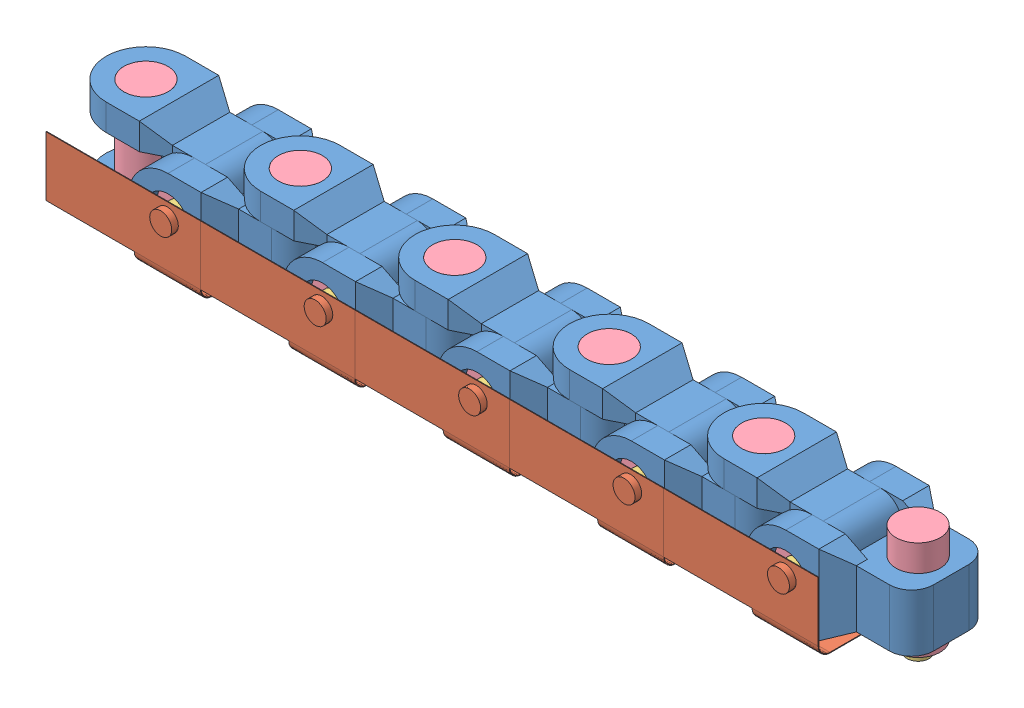
SolidWorks assembly Assem1, configuration Default. Lengths in mm.
Overall size (385.2 53.3 53.3).
48 component instances, 4 part files, 59 mates.
Components (placement in the parent):
- Joint 1-1: Joint 1 [Default] at (-1.5534 8.3861 59.3933) size (68 50 36)
- Joint 1-2: Joint 1 [Default] at (33.4466 33.3861 84.3933) x (1 0 0) z (0 1 0) size (68 50 36)
- Joint 1-3: Joint 1 [Default] at (68.4466 8.3861 59.3933) size (68 50 36)
- Joint 1-4: Joint 1 [Default] at (103.4466 33.3861 84.3933) x (1 0 0) z (0 1 0) size (68 50 36)
- Joint 1-5: Joint 1 [Default] at (138.4466 8.3861 59.3933) size (68 50 36)
- Joint 1-6: Joint 1 [Default] at (173.4466 33.3861 84.3933) x (1 0 0) z (0 1 0) size (68 50 36)
- Joint 1-7: Joint 1 [Default] at (208.4466 8.3861 59.3933) size (68 50 36)
- Joint 1-8: Joint 1 [Default] at (243.4466 33.3861 84.3933) x (1 0 0) z (0 1 0) size (68 50 36)
- Joint 1-9: Joint 1 [Default] at (278.4466 8.3861 59.3933) size (68 50 36)
- Joint 1-10: Joint 1 [Default] at (313.4466 33.3861 84.3933) x (1 0 0) z (0 1 0) size (68 50 36)
- PCB 1-1: PCB 1 [Default] at (264.8403 8.3861 45.5481) x (-1 0 0) z (0 0 1) size (70 35.3 43.3)
- PCB 1-2: PCB 1 [Default] at (194.8403 8.3861 45.5481) x (-1 0 0) z (0 0 1) size (70 35.3 43.3)
- PCB 1-3: PCB 1 [Default] at (124.8403 8.3861 45.5481) x (-1 0 0) z (0 0 1) size (70 35.3 43.3)
- PCB 1-4: PCB 1 [Default] at (54.8403 8.3861 45.5481) x (-1 0 0) z (0 0 1) size (70 35.3 43.3)
- PCB 1-5: PCB 1 [Default] at (-15.1597 8.3861 45.5481) x (-1 0 0) z (0 0 1) size (70 35.3 43.3)
- Magnet and Dowel 1-1: Magnet and Dowel 1 [Default] at (5.0839 18.1514 56.3077) x (-0.837169 0 -0.546944) z (-0.546944 0 0.837169) size (21.97 50 21.97)
  - Magnet 1-1: Magnet 1 [Default] at (3.8689 4.7653 6.2135) size (10 5 10)
  - Dowel 1-1: Dowel 1 [Default] at (3.8689 -40.2347 6.2135) x (0.994608 0 -0.103709) z (0.103709 0 0.994608) size (20 45 20)
- Magnet and Dowel 1-2: Magnet and Dowel 1 [Default] at (285.0839 18.1514 56.3077) x (-0.837169 0 -0.546944) z (-0.546944 0 0.837169) size (21.97 50 21.97)
  - Magnet 1-1: Magnet 1 [Default] at (3.8689 4.7653 6.2135) size (10 5 10)
  - Dowel 1-1: Dowel 1 [Default] at (3.8689 -40.2347 6.2135) x (0.994608 0 -0.103709) z (0.103709 0 0.994608) size (20 45 20)
- Magnet and Dowel 1-3: Magnet and Dowel 1 [Default] at (29.5777 39.5995 74.628) x (1 0 0) z (0 -1 0) size (21.97 50 21.97)
  - Magnet 1-1: Magnet 1 [Default] at (3.8689 4.7653 6.2135) size (10 5 10)
  - Dowel 1-1: Dowel 1 [Default] at (3.8689 -40.2347 6.2135) x (0.994608 0 -0.103709) z (0.103709 0 0.994608) size (20 45 20)
- Magnet and Dowel 1-4: Magnet and Dowel 1 [Default] at (215.0839 18.1514 56.3077) x (-0.837169 0 -0.546944) z (-0.546944 0 0.837169) size (21.97 50 21.97)
  - Magnet 1-1: Magnet 1 [Default] at (3.8689 4.7653 6.2135) size (10 5 10)
  - Dowel 1-1: Dowel 1 [Default] at (3.8689 -40.2347 6.2135) x (0.994608 0 -0.103709) z (0.103709 0 0.994608) size (20 45 20)
- Magnet and Dowel 1-5: Magnet and Dowel 1 [Default] at (75.0839 18.1514 56.3077) x (-0.837169 0 -0.546944) z (-0.546944 0 0.837169) size (21.97 50 21.97)
  - Magnet 1-1: Magnet 1 [Default] at (3.8689 4.7653 6.2135) size (10 5 10)
  - Dowel 1-1: Dowel 1 [Default] at (3.8689 -40.2347 6.2135) x (0.994608 0 -0.103709) z (0.103709 0 0.994608) size (20 45 20)
- Magnet and Dowel 1-6: Magnet and Dowel 1 [Default] at (99.5777 39.5995 74.628) x (1 0 0) z (0 -1 0) size (21.97 50 21.97)
  - Magnet 1-1: Magnet 1 [Default] at (3.8689 4.7653 6.2135) size (10 5 10)
  - Dowel 1-1: Dowel 1 [Default] at (3.8689 -40.2347 6.2135) x (0.994608 0 -0.103709) z (0.103709 0 0.994608) size (20 45 20)
- Magnet and Dowel 1-7: Magnet and Dowel 1 [Default] at (145.0839 18.1514 56.3077) x (-0.837169 0 -0.546944) z (-0.546944 0 0.837169) size (21.97 50 21.97)
  - Magnet 1-1: Magnet 1 [Default] at (3.8689 4.7653 6.2135) size (10 5 10)
  - Dowel 1-1: Dowel 1 [Default] at (3.8689 -40.2347 6.2135) x (0.994608 0 -0.103709) z (0.103709 0 0.994608) size (20 45 20)
- Magnet and Dowel 1-8: Magnet and Dowel 1 [Default] at (169.5777 39.5995 74.628) x (1 0 0) z (0 -1 0) size (21.97 50 21.97)
  - Magnet 1-1: Magnet 1 [Default] at (3.8689 4.7653 6.2135) size (10 5 10)
  - Dowel 1-1: Dowel 1 [Default] at (3.8689 -40.2347 6.2135) x (0.994608 0 -0.103709) z (0.103709 0 0.994608) size (20 45 20)
- Magnet and Dowel 1-10: Magnet and Dowel 1 [Default] at (239.5777 39.5995 74.628) x (1 0 0) z (0 -1 0) size (21.97 50 21.97)
  - Magnet 1-1: Magnet 1 [Default] at (3.8689 4.7653 6.2135) size (10 5 10)
  - Dowel 1-1: Dowel 1 [Default] at (3.8689 -40.2347 6.2135) x (0.994608 0 -0.103709) z (0.103709 0 0.994608) size (20 45 20)
- Magnet and Dowel 1-11: Magnet and Dowel 1 [Default] at (309.5777 39.5995 74.628) x (1 0 0) z (0 -1 0) size (21.97 50 21.97)
  - Magnet 1-1: Magnet 1 [Default] at (3.8689 4.7653 6.2135) size (10 5 10)
  - Dowel 1-1: Dowel 1 [Default] at (3.8689 -40.2347 6.2135) x (0.994608 0 -0.103709) z (0.103709 0 0.994608) size (20 45 20)
- Magnet and Dowel 1-12: Magnet and Dowel 1 [Default] at (355.0839 18.1514 56.3077) x (-0.837169 0 -0.546944) z (-0.546944 0 0.837169) size (21.97 50 21.97)
  - Magnet 1-1: Magnet 1 [Default] at (3.8689 4.7653 6.2135) size (10 5 10)
  - Dowel 1-1: Dowel 1 [Default] at (3.8689 -40.2347 6.2135) x (0.994608 0 -0.103709) z (0.103709 0 0.994608) size (20 45 20)
Mates (geometry in assembly coordinates):
- Concentric1: concentric anti-aligned: cylinder of Joint 1-1 through (33.4466 33.3861 91.3933) axis (0 0 -1) radius 10; cylinder of Joint 1-2 through (33.4466 33.3861 34.3933) axis (0 0 1) radius 10
- Concentric2: concentric aligned: cylinder of Joint 1-2 through (68.4466 65.3861 59.3933) axis (0 -1 0) radius 10; cylinder of Joint 1-3 through (68.4466 58.3861 59.3933) axis (0 -1 0) radius 10
- Coincident1: coincident anti-aligned: plane of Joint 1-1 through (23.4466 8.3861 72.3933) normal (0 0 1); plane of Joint 1-2 through (53.4466 65.3861 72.3933) normal (0 0 -1)
- Coincident2: coincident anti-aligned: plane of Joint 1-2 through (58.4466 46.3861 84.3933) normal (0 1 0); plane of Joint 1-3 through (88.4466 46.3861 91.3933) normal (0 -1 0)
- Concentric3: concentric anti-aligned: cylinder of Joint 1-3 through (103.4466 33.3861 91.3933) axis (0 0 -1) radius 10; cylinder of Joint 1-4 through (103.4466 33.3861 34.3933) axis (0 0 1) radius 10
- Coincident3: coincident anti-aligned: plane of Joint 1-3 through (93.4466 8.3861 46.3933) normal (0 0 -1); plane of Joint 1-4 through (123.4466 65.3861 46.3933) normal (0 0 1)
- Coincident4: coincident anti-aligned: plane of Joint 1-4 through (128.4466 46.3861 84.3933) normal (0 1 0); plane of Joint 1-5 through (158.4466 46.3861 91.3933) normal (0 -1 0)
- Concentric4: concentric aligned: cylinder of Joint 1-4 through (138.4466 65.3861 59.3933) axis (0 -1 0) radius 10; cylinder of Joint 1-5 through (138.4466 58.3861 59.3933) axis (0 -1 0) radius 10
- Concentric5: concentric anti-aligned: cylinder of Joint 1-5 through (173.4466 33.3861 91.3933) axis (0 0 -1) radius 10; cylinder of Joint 1-6 through (173.4466 33.3861 34.3933) axis (0 0 1) radius 10
- Coincident5: coincident anti-aligned: plane of Joint 1-5 through (163.4466 8.3861 46.3933) normal (0 0 -1); plane of Joint 1-6 through (193.4466 65.3861 46.3933) normal (0 0 1)
- Coincident6: coincident anti-aligned: plane of Joint 1-6 through (198.4466 46.3861 84.3933) normal (0 1 0); plane of Joint 1-7 through (228.4466 46.3861 91.3933) normal (0 -1 0)
- Concentric6: concentric aligned: cylinder of Joint 1-6 through (208.4466 65.3861 59.3933) axis (0 -1 0) radius 10; cylinder of Joint 1-7 through (208.4466 58.3861 59.3933) axis (0 -1 0) radius 10
- Concentric7: concentric anti-aligned: cylinder of Joint 1-7 through (243.4466 33.3861 91.3933) axis (0 0 -1) radius 10; cylinder of Joint 1-8 through (243.4466 33.3861 34.3933) axis (0 0 1) radius 10
- Coincident7: coincident anti-aligned: plane of Joint 1-7 through (233.4466 8.3861 46.3933) normal (0 0 -1); plane of Joint 1-8 through (263.4466 65.3861 46.3933) normal (0 0 1)
- Concentric8: concentric aligned: cylinder of Joint 1-8 through (278.4466 65.3861 59.3933) axis (0 -1 0) radius 10; cylinder of Joint 1-9 through (278.4466 58.3861 59.3933) axis (0 -1 0) radius 10
- Coincident8: coincident anti-aligned: plane of Joint 1-8 through (268.4466 46.3861 84.3933) normal (0 1 0); plane of Joint 1-9 through (298.4466 46.3861 91.3933) normal (0 -1 0)
- Concentric9: concentric anti-aligned: cylinder of Joint 1-9 through (313.4466 33.3861 91.3933) axis (0 0 -1) radius 10; cylinder of Joint 1-10 through (313.4466 33.3861 34.3933) axis (0 0 1) radius 10
- Coincident9: coincident anti-aligned: plane of Joint 1-9 through (303.4466 8.3861 46.3933) normal (0 0 -1); plane of Joint 1-10 through (333.4466 65.3861 46.3933) normal (0 0 1)
- Parallel1: parallel aligned: plane of Joint 1-9 through (278.4466 8.3861 59.3933) normal (0 -1 0); plane of Joint 1-10 through (338.4466 20.3861 84.3933) normal (0 -1 0)
- Coincident11: coincident aligned: plane of Joint 1-7 through (208.4466 8.3861 59.3933) normal (0 -1 0); plane of Joint 1-9 through (278.4466 8.3861 59.3933) normal (0 -1 0)
- Coincident12: coincident aligned: plane of Joint 1-5 through (138.4466 8.3861 59.3933) normal (0 -1 0); plane of Joint 1-7 through (208.4466 8.3861 59.3933) normal (0 -1 0)
- Coincident13: coincident aligned: plane of Joint 1-3 through (68.4466 8.3861 59.3933) normal (0 -1 0); plane of Joint 1-5 through (138.4466 8.3861 59.3933) normal (0 -1 0)
- Coincident14: coincident aligned: plane of Joint 1-1 through (-1.5534 8.3861 59.3933) normal (0 -1 0); plane of Joint 1-3 through (68.4466 8.3861 59.3933) normal (0 -1 0)
- Coincident15: coincident aligned: plane of Joint 1-2 through (33.4466 33.3861 84.3933) normal (0 0 1); plane of Joint 1-4 through (103.4466 33.3861 84.3933) normal (0 0 1)
- Coincident16: coincident aligned: plane of Joint 1-4 through (103.4466 33.3861 84.3933) normal (0 0 1); plane of Joint 1-6 through (173.4466 33.3861 84.3933) normal (0 0 1)
- Coincident17: coincident aligned: plane of Joint 1-6 through (173.4466 33.3861 84.3933) normal (0 0 1); plane of Joint 1-8 through (243.4466 33.3861 84.3933) normal (0 0 1)
- Coincident18: coincident aligned: plane of Joint 1-8 through (243.4466 33.3861 84.3933) normal (0 0 1); plane of Joint 1-10 through (313.4466 33.3861 84.3933) normal (0 0 1)
- Concentric10: concentric anti-aligned: cylinder of Joint 1-10 through (313.4466 33.3861 34.3933) axis (0 0 1) radius 10; cylinder of PCB 1-1 through (313.4466 33.3861 87.6933) axis (0 0 -1) radius 5
- Concentric11: concentric anti-aligned: cylinder of Joint 1-9 through (278.4466 58.3861 59.3933) axis (0 -1 0) radius 10; cylinder of PCB 1-1 through (278.4466 5.0861 59.3933) axis (0 1 0) radius 5
- Concentric12: concentric anti-aligned: cylinder of Joint 1-7 through (208.4466 58.3861 59.3933) axis (0 -1 0) radius 10; cylinder of PCB 1-2 through (208.4466 5.0861 59.3933) axis (0 1 0) radius 5
- Concentric13: concentric anti-aligned: cylinder of PCB 1-2 through (243.4466 33.3861 87.6933) axis (0 0 -1) radius 5; cylinder of Joint 1-8 through (243.4466 33.3861 34.3933) axis (0 0 1) radius 10
- Concentric14: concentric anti-aligned: cylinder of PCB 1-3 through (173.4466 33.3861 87.6933) axis (0 0 -1) radius 5; cylinder of Joint 1-6 through (173.4466 33.3861 34.3933) axis (0 0 1) radius 10
- Concentric16: concentric anti-aligned: cylinder of Joint 1-5 through (138.4466 58.3861 59.3933) axis (0 -1 0) radius 10; cylinder of PCB 1-3 through (138.4466 5.0861 59.3933) axis (0 1 0) radius 5
- Concentric17: concentric anti-aligned: cylinder of Joint 1-4 through (103.4466 33.3861 34.3933) axis (0 0 1) radius 10; cylinder of PCB 1-4 through (103.4466 33.3861 87.6933) axis (0 0 -1) radius 5
- Concentric18: concentric anti-aligned: cylinder of Joint 1-3 through (68.4466 58.3861 59.3933) axis (0 -1 0) radius 10; cylinder of PCB 1-4 through (68.4466 5.0861 59.3933) axis (0 1 0) radius 5
- Concentric21: concentric anti-aligned: cylinder of Joint 1-2 through (33.4466 33.3861 34.3933) axis (0 0 1) radius 10; cylinder of PCB 1-5 through (33.4466 33.3861 87.6933) axis (0 0 -1) radius 5
- Concentric22: concentric anti-aligned: cylinder of Joint 1-1 through (-1.5534 58.3861 59.3933) axis (0 -1 0) radius 10; cylinder of PCB 1-5 through (-1.5534 5.0861 59.3933) axis (0 1 0) radius 5
- Concentric23: concentric anti-aligned: cylinder of Joint 1-1 through (-1.5534 58.3861 59.3933) axis (0 -1 0) radius 10; cylinder of Magnet and Dowel 1-1/Dowel 1-1 through (-1.5534 13.3861 59.3933) axis (0 1 0) radius 10
- Coincident19: coincident aligned: plane of Joint 1-1 through (-1.5534 58.3861 59.3933) normal (0 1 0); plane of Magnet and Dowel 1-1/Dowel 1-1 through (-1.5534 58.3861 59.3933) normal (0 1 0)
- Concentric26: concentric: cylinder of Joint 1-3 through (68.4466 58.3861 59.3933) axis (0 -1 0) radius 10; cylinder of Magnet and Dowel 1-5/Dowel 1-1 through (68.4466 13.3861 59.3933) axis (0 1 0) radius 10
- Coincident21: coincident aligned: plane of Joint 1-3 through (68.4466 58.3861 59.3933) normal (0 1 0); plane of Magnet and Dowel 1-5/Dowel 1-1 through (68.4466 58.3861 59.3933) normal (0 1 0)
- Concentric27: concentric: cylinder of Joint 1-5 through (138.4466 58.3861 59.3933) axis (0 -1 0) radius 10; cylinder of Magnet and Dowel 1-7/Dowel 1-1 through (138.4466 13.3861 59.3933) axis (0 1 0) radius 10
- Coincident22: coincident aligned: plane of Joint 1-5 through (138.4466 58.3861 59.3933) normal (0 1 0); plane of Magnet and Dowel 1-7/Dowel 1-1 through (138.4466 58.3861 59.3933) normal (0 1 0)
- Concentric28: concentric: cylinder of Joint 1-7 through (208.4466 58.3861 59.3933) axis (0 -1 0) radius 10; cylinder of Magnet and Dowel 1-4/Dowel 1-1 through (208.4466 13.3861 59.3933) axis (0 1 0) radius 10
- Coincident23: coincident aligned: plane of Joint 1-7 through (208.4466 58.3861 59.3933) normal (0 1 0); plane of Magnet and Dowel 1-4/Dowel 1-1 through (208.4466 58.3861 59.3933) normal (0 1 0)
- Concentric29: concentric: cylinder of Joint 1-9 through (278.4466 58.3861 59.3933) axis (0 -1 0) radius 10; cylinder of Magnet and Dowel 1-2/Dowel 1-1 through (278.4466 13.3861 59.3933) axis (0 1 0) radius 10
- Coincident24: coincident aligned: plane of Joint 1-9 through (278.4466 58.3861 59.3933) normal (0 1 0); plane of Magnet and Dowel 1-2/Dowel 1-1 through (278.4466 58.3861 59.3933) normal (0 1 0)
- Concentric30: concentric: cylinder of Joint 1-2 through (33.4466 33.3861 34.3933) axis (0 0 1) radius 10; cylinder of Magnet and Dowel 1-3/Dowel 1-1 through (33.4466 33.3861 79.3933) axis (0 0 -1) radius 10
- Coincident25: coincident aligned: plane of Joint 1-2 through (33.4466 33.3861 34.3933) normal (0 0 -1); plane of Magnet and Dowel 1-3/Dowel 1-1 through (33.4466 33.3861 34.3933) normal (0 0 -1)
- Concentric31: concentric: cylinder of Joint 1-4 through (103.4466 33.3861 34.3933) axis (0 0 1) radius 10; cylinder of Magnet and Dowel 1-6/Dowel 1-1 through (103.4466 33.3861 79.3933) axis (0 0 -1) radius 10
- Coincident26: coincident aligned: plane of Joint 1-4 through (103.4466 33.3861 34.3933) normal (0 0 -1); plane of Magnet and Dowel 1-6/Dowel 1-1 through (103.4466 33.3861 34.3933) normal (0 0 -1)
- Concentric32: concentric: cylinder of Joint 1-6 through (173.4466 33.3861 34.3933) axis (0 0 1) radius 10; cylinder of Magnet and Dowel 1-8/Dowel 1-1 through (173.4466 33.3861 79.3933) axis (0 0 -1) radius 10
- Coincident27: coincident aligned: plane of Joint 1-6 through (173.4466 33.3861 34.3933) normal (0 0 -1); plane of Magnet and Dowel 1-8/Dowel 1-1 through (173.4466 33.3861 34.3933) normal (0 0 -1)
- Concentric33: concentric: cylinder of Joint 1-8 through (243.4466 33.3861 34.3933) axis (0 0 1) radius 10; cylinder of Magnet and Dowel 1-10/Dowel 1-1 through (243.4466 33.3861 79.3933) axis (0 0 -1) radius 10
- Coincident28: coincident aligned: plane of Joint 1-8 through (243.4466 33.3861 34.3933) normal (0 0 -1); plane of Magnet and Dowel 1-10/Dowel 1-1 through (243.4466 33.3861 34.3933) normal (0 0 -1)
- Concentric34: concentric: cylinder of Joint 1-10 through (313.4466 33.3861 34.3933) axis (0 0 1) radius 10; cylinder of Magnet and Dowel 1-11/Dowel 1-1 through (313.4466 33.3861 79.3933) axis (0 0 -1) radius 10
- Coincident29: coincident aligned: plane of Joint 1-10 through (313.4466 33.3861 34.3933) normal (0 0 -1); plane of Magnet and Dowel 1-11/Dowel 1-1 through (313.4466 33.3861 34.3933) normal (0 0 -1)
- Concentric35: concentric: cylinder of Joint 1-10 through (348.4466 65.3861 59.3933) axis (0 -1 0) radius 10; cylinder of Magnet and Dowel 1-12/Dowel 1-1 through (348.4466 13.3861 59.3933) axis (0 1 0) radius 10
- Coincident30: coincident aligned: plane of Joint 1-9 through (278.4466 58.3861 59.3933) normal (0 1 0); plane of Magnet and Dowel 1-12/Dowel 1-1 through (348.4466 58.3861 59.3933) normal (0 1 0)
